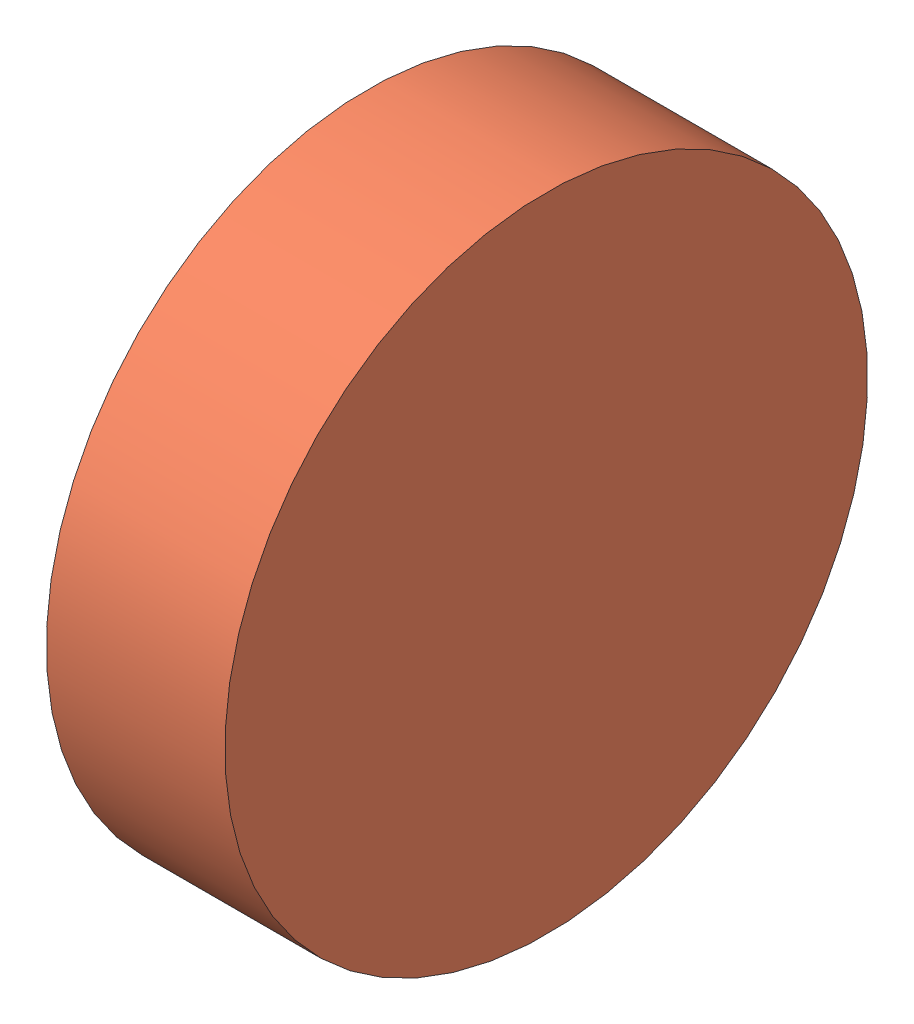
SolidWorks assembly Assem2, configuration Default. Lengths in mm.
Overall size (7 24.76 24.76).
2 component instances, 2 part files, 2 mates.
Components (placement in the parent):
- M4 Nut-1: M4 Nut [Default] at (0.7218 4.5119 7.2156) size (3.68 8.08 7)
- New Motor roller-1: New Motor roller [Default] at (-1.6782 4.4817 6.9338) x (0 0.524097 -0.851658) z (1 0 0) size (18 18 7)
Mates (geometry in assembly coordinates):
- Coincident1: coincident anti-aligned: plane of M4 Nut-1 through (2.3218 4.5119 7.2156) normal (1 0 0); plane of New Motor roller-1 through (2.3218 4.4817 6.9338) normal (-1 0 0)
- Parallel1: parallel anti-aligned: plane of M4 Nut-1 through (2.3218 6.5326 10.7156) normal (0 0 1); plane of New Motor roller-1 through (0.3218 6.5891 10.5838) normal (0 0 -1)
